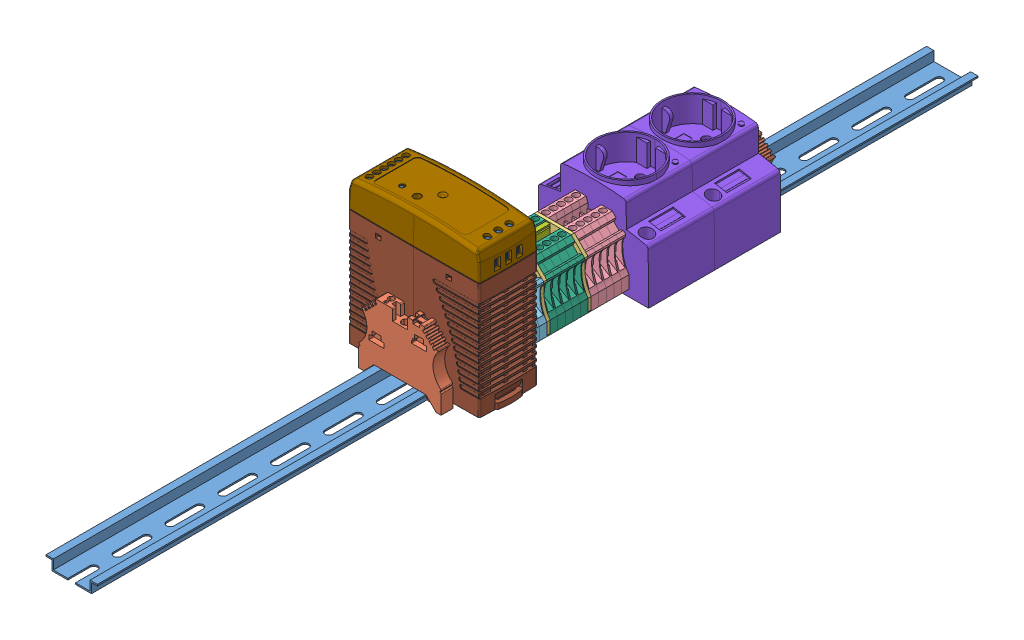
SolidWorks assembly 5xLNPE_Schuko-Raspi, configuration Standard. Lengths in mm.
Overall size (91.72 108.8 600).
29 component instances, 11 part files, 81 mates.
Components (placement in the parent):
- Hutschiene-1: Hutschiene [600] at (-17.5 -7.5 -600) size (35 7.5 600)
- WEW_35_2-1: WEW_35_2 [Standard] at (-45.75 -7 -453.6811) x (0 0 1) z (0 1 0) size (8 56.1 46.5)
- WEW_35_2-2: WEW_35_2 [Standard] at (10.35 -7 -223.8311) x (0 0 -1) z (0 1 0) size (8 56.1 46.5)
- D_UT_2.5_10-1: D_UT_2.5_10 [Standard] at (-46.4297 58.45 -274.0311) size (47 39.8 2.2)
- D_UT_2.5_10-2: D_UT_2.5_10 [Standard] at (-46.4297 58.45 -301.9811) size (47 39.8 2.2)
- D_UT_2.5_10-3: D_UT_2.5_10 [Standard] at (-46.4297 58.45 -329.9311) size (47 39.8 2.2)
- UT_2.5_PE-1: UT_2.5_PE [Standard] at (-48.6989 10.6178 -329.9311) x (0.992546 -0.121869 0) z (0 0 1) size (49.27 50.96 5.15)
- UT_2.5_PE-2: UT_2.5_PE [Standard] at (-48.6989 10.6178 -335.0811) x (0.992546 -0.121869 0) z (0 0 1) size (49.27 50.96 5.15)
- UT_2.5_PE-3: UT_2.5_PE [Standard] at (-48.6989 10.6178 -340.2311) x (0.992546 -0.121869 0) z (0 0 1) size (49.27 50.96 5.15)
- UT_2.5_PE-4: UT_2.5_PE [Standard] at (-48.6989 10.6178 -345.3811) x (0.992546 -0.121869 0) z (0 0 1) size (49.27 50.96 5.15)
- UT_2.5_PE-5: UT_2.5_PE [Standard] at (-48.6989 10.6178 -350.5311) x (0.992546 -0.121869 0) z (0 0 1) size (49.27 50.96 5.15)
- UT_2.5-1: UT_2.5 [Standard] at (-48.6989 10.6178 -274.0311) x (0.992546 -0.121869 0) z (0 0 1) size (49.27 50.96 5.15)
- UT_2.5-2: UT_2.5 [Standard] at (-48.6989 10.6178 -279.1811) x (0.992546 -0.121869 0) z (0 0 1) size (49.27 50.96 5.15)
- UT_2.5-3: UT_2.5 [Standard] at (-48.6989 10.6178 -284.3311) x (0.992546 -0.121869 0) z (0 0 1) size (49.27 50.96 5.15)
- UT_2.5-4: UT_2.5 [Standard] at (-48.6989 10.6178 -289.4811) x (0.992546 -0.121869 0) z (0 0 1) size (49.27 50.96 5.15)
- UT_2.5-5: UT_2.5 [Standard] at (-48.6989 10.6178 -294.6311) x (0.992546 -0.121869 0) z (0 0 1) size (49.27 50.96 5.15)
- UT_2.5_BU-1: UT_2.5_BU [Standard] at (-48.6989 10.6178 -301.9811) x (0.992546 -0.121869 0) z (0 0 1) size (49.27 50.96 5.15)
- UT_2.5_BU-2: UT_2.5_BU [Standard] at (-48.6989 10.6178 -307.1311) x (0.992546 -0.121869 0) z (0 0 1) size (49.27 50.96 5.15)
- UT_2.5_BU-3: UT_2.5_BU [Standard] at (-48.6989 10.6178 -312.2811) x (0.992546 -0.121869 0) z (0 0 1) size (49.27 50.96 5.15)
- UT_2.5_BU-4: UT_2.5_BU [Standard] at (-48.6989 10.6178 -317.4311) x (0.992546 -0.121869 0) z (0 0 1) size (49.27 50.96 5.15)
- UT_2.5_BU-5: UT_2.5_BU [Standard] at (-48.6989 10.6178 -322.5811) x (0.992546 -0.121869 0) z (0 0 1) size (49.27 50.96 5.15)
- FBS_5_5-1: FBS_5_5 [Standard] at (-24.1072 48.875 -332.8661) size (3 22.98 24.6)
- FBS_5_5-2: FBS_5_5 [Standard] at (-24.1072 48.875 -360.8161) size (3 22.98 24.6)
- EO_CF_UT_LED-1: EO_CF_UT_LED [Standard] at (-87.0914 -21.0563 -380.4311) size (75.48 61.64 45)
- EO_CF_UT_LED-2: EO_CF_UT_LED [Standard] at (-87.0914 -21.0563 -425.4311) size (75.48 61.64 45)
- MDR-40&60-1: MDR-40&60 [Standard] at (-16.4956 35.1498 -251.6915) x (0 0 1) z (0 1 0) size (40 91.72 100.24)
  - Skin_Group1-1: Skin_Group1 [Standard] at origin size (40 89.9 28.74)
  - 3P-CONECT-1: 3P-CONECT [Standard] at (-7.6496 -37.3548 41.6035) x (-1 0 0) z (0 1 0) size (34.1 93.54 85.1)
  - Skin_Group1.1-1: Skin_Group1.1 [Standard] at origin size (40 91.72 79.25)
Mates (geometry in assembly coordinates):
- Deckungsgleich1: coincident aligned: plane of Hutschiene-1 through (-17.5 -7.5 0) normal (0 0 1); plane of assembly through (0 0 0) normal (0 0 1)
- Deckungsgleich2: coincident aligned: plane of Hutschiene-1 through (-30 0 0) normal (0 1 0); plane of assembly through (0 0 0) normal (0 1 0)
- Deckungsgleich3: coincident aligned: plane of Hutschiene-1 through (0 -1 0) normal (1 0 0); plane of assembly through (0 0 0) normal (1 0 0)
- Deckungsgleich70: coincident anti-aligned: plane of Hutschiene-1 through (0 0 0) normal (0 1 0); plane of EO_CF_UT_LED-1 through (-54.05 0 -382.5811) normal (0 -1 0)
- Deckungsgleich71: coincident anti-aligned: plane of Hutschiene-1 through (-30 0 0) normal (0 1 0); plane of EO_CF_UT_LED-2 through (-54.05 0 -427.5811) normal (0 -1 0)
- Deckungsgleich72: coincident anti-aligned: plane of Hutschiene-1 through (-30 0 0) normal (0 1 0); plane of ? through (-54.05 0 -283.75) normal (0 -1 0)
- Deckungsgleich73: coincident anti-aligned: plane of Hutschiene-1 through (0 -1 0) normal (1 0 0); plane of EO_CF_UT_LED-1 through (0 8.9 -356.6811) normal (-1 0 0)
- Deckungsgleich74: coincident anti-aligned: plane of Hutschiene-1 through (0 -1 0) normal (1 0 0); plane of EO_CF_UT_LED-2 through (0 8.9 -401.6811) normal (-1 0 0)
- Deckungsgleich75: coincident anti-aligned: plane of Hutschiene-1 through (0 -1 0) normal (1 0 0); plane of ? through (0 8.9 -257.85) normal (-1 0 0)
- Deckungsgleich77: coincident anti-aligned: plane of EO_CF_UT_LED-1 through (-17.75 2.45 -400.6811) normal (0 0 -1); plane of EO_CF_UT_LED-2 through (-17.75 2.45 -400.6811) normal (0 0 1)
- Deckungsgleich78: coincident anti-aligned: plane of EO_CF_UT_LED-2 through (-17.75 2.45 -256.85) normal (0 0 -1); plane of ? through (-17.75 2.45 -256.85) normal (0 0 1)
- Deckungsgleich81: coincident anti-aligned: plane of Hutschiene-1 through (-30 0 0) normal (0 1 0); plane of WEW_35_2-2 through (-14.3966 13.4591 -231.876) normal (0 -1 0)
- Deckungsgleich82: coincident anti-aligned: plane of Hutschiene-1 through (-30 0 0) normal (0 1 0); plane of UT_2.5-1 through (-7.7 0 -274.0311) normal (0 -1 0)
- Deckungsgleich83: coincident anti-aligned: plane of Hutschiene-1 through (-30 0 0) normal (0 1 0); plane of UT_2.5-2 through (-7.7 0 -279.1811) normal (0 -1 0)
- Deckungsgleich84: coincident anti-aligned: plane of Hutschiene-1 through (-30 0 0) normal (0 1 0); plane of UT_2.5-3 through (-7.7 0 -284.3311) normal (0 -1 0)
- Deckungsgleich85: coincident anti-aligned: plane of Hutschiene-1 through (-30 0 0) normal (0 1 0); plane of UT_2.5-4 through (-7.7 0 -289.4811) normal (0 -1 0)
- Deckungsgleich86: coincident anti-aligned: plane of Hutschiene-1 through (-30 0 0) normal (0 1 0); plane of UT_2.5-5 through (-7.7 0 -294.6311) normal (0 -1 0)
- Deckungsgleich87: coincident aligned: plane of D_UT_2.5_10-1 through (4.3 30.8 -272.9311) normal (1 0 0); plane of UT_2.5-1 through (4.3 30.8 -274.0311) normal (1 0 0)
- Deckungsgleich88: coincident aligned: line of D_UT_2.5_10-1 through (4.3 29.6 -274.0311) axis (0 0 1); line of UT_2.5-1 through (4.3 29.6 -279.1811) axis (0 0 1)
- Deckungsgleich89: coincident anti-aligned: plane of D_UT_2.5_10-1 through (8.926 -3.78 -274.0311) normal (0 0 -1); plane of UT_2.5-1 through (0 0 -274.0311) normal (0 0 1)
- Deckungsgleich90: coincident anti-aligned: plane of UT_2.5-1 through (0 0 -279.1811) normal (0 0 -1); plane of UT_2.5-2 through (0 0 -279.1811) normal (0 0 1)
- Deckungsgleich91: coincident anti-aligned: plane of UT_2.5-2 through (0 0 -284.3311) normal (0 0 -1); plane of UT_2.5-3 through (0 0 -284.3311) normal (0 0 1)
- Deckungsgleich92: coincident anti-aligned: plane of UT_2.5-3 through (0 0 -289.4811) normal (0 0 -1); plane of UT_2.5-4 through (0 0 -289.4811) normal (0 0 1)
- Deckungsgleich93: coincident anti-aligned: plane of UT_2.5-4 through (0 0 -294.6311) normal (0 0 -1); plane of UT_2.5-5 through (0 0 -294.6311) normal (0 0 1)
- Deckungsgleich94: coincident anti-aligned: plane of Hutschiene-1 through (0 -1 0) normal (1 0 0); plane of UT_2.5-1 through (0 -1.1 -274.0311) normal (-1 0 0)
- Deckungsgleich95: coincident anti-aligned: plane of Hutschiene-1 through (0 -1 0) normal (1 0 0); plane of UT_2.5-2 through (0 -1.1 -279.1811) normal (-1 0 0)
- Deckungsgleich96: coincident anti-aligned: plane of Hutschiene-1 through (0 -1 0) normal (1 0 0); plane of UT_2.5-3 through (0 -1.1 -284.3311) normal (-1 0 0)
- Deckungsgleich97: coincident anti-aligned: plane of Hutschiene-1 through (0 -1 0) normal (1 0 0); plane of UT_2.5-4 through (0 -1.1 -289.4811) normal (-1 0 0)
- Deckungsgleich98: coincident anti-aligned: plane of Hutschiene-1 through (0 -1 0) normal (1 0 0); plane of UT_2.5-5 through (0 -1.1 -294.6311) normal (-1 0 0)
- Deckungsgleich101: coincident: plane of Hutschiene-1 through (0 -1 0) normal (1 0 0); line of WEW_35_2-2 through (21.0034 13.4591 -231.876) axis (0 0 1)
- Deckungsgleich102: coincident anti-aligned: plane of UT_2.5-1 through (-18.35 21.85 -274.5061) normal (0 0 -1); plane of FBS_5_5-1 through (-18.5 39.7 -274.5061) normal (0 0 1)
- Deckungsgleich103: coincident anti-aligned: plane of UT_2.5-2 through (-21.5 36.703 -279.1811) normal (1 0 0); plane of FBS_5_5-1 through (-21.5 38.7586 -288.4406) normal (-1 0 0)
- Deckungsgleich104: coincident aligned: plane of UT_2.5-1 through (-30.1 40 -274.0311) normal (0 1 0); plane of FBS_5_5-1 through (-18.5 40 -284.9061) normal (0 1 0)
- Deckungsgleich105: coincident anti-aligned: plane of D_UT_2.5_10-2 through (8.926 -3.78 -301.9811) normal (0 0 -1); plane of UT_2.5_BU-1 through (0 0 -301.9811) normal (0 0 1)
- Deckungsgleich106: coincident anti-aligned: plane of UT_2.5_BU-1 through (0 0 -307.1311) normal (0 0 -1); plane of UT_2.5_BU-2 through (0 0 -307.1311) normal (0 0 1)
- Deckungsgleich107: coincident anti-aligned: plane of UT_2.5_BU-2 through (0 0 -312.2811) normal (0 0 -1); plane of UT_2.5_BU-3 through (0 0 -312.2811) normal (0 0 1)
- Deckungsgleich108: coincident anti-aligned: plane of UT_2.5_BU-3 through (0 0 -317.4311) normal (0 0 -1); plane of UT_2.5_BU-4 through (0 0 -317.4311) normal (0 0 1)
- Deckungsgleich109: coincident anti-aligned: plane of UT_2.5_BU-4 through (0 0 -322.5811) normal (0 0 -1); plane of UT_2.5_BU-5 through (0 0 -322.5811) normal (0 0 1)
- Deckungsgleich110: coincident anti-aligned: plane of Hutschiene-1 through (-30 0 0) normal (0 1 0); plane of UT_2.5_BU-1 through (-7.7 0 -301.9811) normal (0 -1 0)
- Deckungsgleich111: coincident anti-aligned: plane of Hutschiene-1 through (-30 0 0) normal (0 1 0); plane of UT_2.5_BU-2 through (-7.7 0 -307.1311) normal (0 -1 0)
- Deckungsgleich112: coincident anti-aligned: plane of Hutschiene-1 through (-30 0 0) normal (0 1 0); plane of UT_2.5_BU-3 through (-7.7 0 -312.2811) normal (0 -1 0)
- Deckungsgleich113: coincident anti-aligned: plane of Hutschiene-1 through (-30 0 0) normal (0 1 0); plane of UT_2.5_BU-4 through (-7.7 0 -317.4311) normal (0 -1 0)
- Deckungsgleich114: coincident anti-aligned: plane of Hutschiene-1 through (-30 0 0) normal (0 1 0); plane of UT_2.5_BU-5 through (-7.7 0 -322.5811) normal (0 -1 0)
- Deckungsgleich115: coincident aligned: plane of D_UT_2.5_10-2 through (4.3 30.8 -300.8811) normal (1 0 0); plane of UT_2.5_BU-1 through (4.3 30.8 -301.9811) normal (1 0 0)
- Deckungsgleich116: coincident aligned: line of D_UT_2.5_10-2 through (4.3 29.6 -301.9811) axis (0 0 1); line of UT_2.5_BU-1 through (4.3 29.6 -307.1311) axis (0 0 1)
- Deckungsgleich117: coincident anti-aligned: plane of Hutschiene-1 through (0 -1 0) normal (1 0 0); plane of UT_2.5_BU-1 through (0 -1.1 -301.9811) normal (-1 0 0)
- Deckungsgleich118: coincident anti-aligned: plane of Hutschiene-1 through (0 -1 0) normal (1 0 0); plane of UT_2.5_BU-2 through (0 -1.1 -307.1311) normal (-1 0 0)
- Deckungsgleich119: coincident anti-aligned: plane of Hutschiene-1 through (0 -1 0) normal (1 0 0); plane of UT_2.5_BU-3 through (0 -1.1 -312.2811) normal (-1 0 0)
- Deckungsgleich120: coincident anti-aligned: plane of Hutschiene-1 through (0 -1 0) normal (1 0 0); plane of UT_2.5_BU-4 through (0 -1.1 -317.4311) normal (-1 0 0)
- Deckungsgleich121: coincident anti-aligned: plane of Hutschiene-1 through (0 -1 0) normal (1 0 0); plane of UT_2.5_BU-5 through (0 -1.1 -322.5811) normal (-1 0 0)
- Deckungsgleich122: coincident anti-aligned: plane of D_UT_2.5_10-2 through (-31.3534 31.331 -299.7811) normal (0 0 1); plane of UT_2.5-5 through (0 0 -299.7811) normal (0 0 -1)
- Deckungsgleich123: coincident anti-aligned: plane of UT_2.5_BU-1 through (-18.35 21.85 -302.4561) normal (0 0 -1); plane of FBS_5_5-2 through (-18.5 39.7 -302.4561) normal (0 0 1)
- Deckungsgleich124: coincident anti-aligned: plane of UT_2.5_BU-1 through (-21.5 36.703 -301.9811) normal (1 0 0); plane of FBS_5_5-2 through (-21.5 38.7586 -316.3906) normal (-1 0 0)
- Deckungsgleich125: coincident aligned: plane of UT_2.5_BU-1 through (-30.1 40 -301.9811) normal (0 1 0); plane of FBS_5_5-2 through (-18.5 40 -312.8561) normal (0 1 0)
- Deckungsgleich126: coincident anti-aligned: plane of D_UT_2.5_10-3 through (8.926 -3.78 -329.9311) normal (0 0 -1); plane of UT_2.5_PE-1 through (0 0 -329.9311) normal (0 0 1)
- Deckungsgleich127: coincident anti-aligned: plane of UT_2.5_PE-1 through (0 0 -335.0811) normal (0 0 -1); plane of UT_2.5_PE-2 through (0 0 -335.0811) normal (0 0 1)
- Deckungsgleich128: coincident anti-aligned: plane of UT_2.5_PE-2 through (0 0 -340.2311) normal (0 0 -1); plane of UT_2.5_PE-3 through (0 0 -340.2311) normal (0 0 1)
- Deckungsgleich129: coincident anti-aligned: plane of UT_2.5_PE-3 through (0 0 -345.3811) normal (0 0 -1); plane of UT_2.5_PE-4 through (0 0 -345.3811) normal (0 0 1)
- Deckungsgleich130: coincident anti-aligned: plane of UT_2.5_PE-4 through (0 0 -350.5311) normal (0 0 -1); plane of UT_2.5_PE-5 through (0 0 -350.5311) normal (0 0 1)
- Deckungsgleich131: coincident aligned: plane of D_UT_2.5_10-3 through (4.3 30.8 -328.8311) normal (1 0 0); plane of UT_2.5_PE-1 through (4.3 30.8 -329.9311) normal (1 0 0)
- Deckungsgleich132: coincident aligned: line of D_UT_2.5_10-3 through (4.3 30.8 -329.9311) axis (0 0 1); line of UT_2.5_PE-1 through (4.3 30.8 -335.0811) axis (0 0 1)
- Deckungsgleich133: coincident anti-aligned: plane of Hutschiene-1 through (-30 0 0) normal (0 1 0); plane of UT_2.5_PE-5 through (-7.7 0 -350.5311) normal (0 -1 0)
- Deckungsgleich134: coincident anti-aligned: plane of Hutschiene-1 through (-30 0 0) normal (0 1 0); plane of UT_2.5_PE-4 through (-7.7 0 -345.3811) normal (0 -1 0)
- Deckungsgleich135: coincident anti-aligned: plane of Hutschiene-1 through (-30 0 0) normal (0 1 0); plane of UT_2.5_PE-3 through (-7.7 0 -340.2311) normal (0 -1 0)
- Deckungsgleich136: coincident anti-aligned: plane of Hutschiene-1 through (-30 0 0) normal (0 1 0); plane of UT_2.5_PE-2 through (-7.7 0 -335.0811) normal (0 -1 0)
- Deckungsgleich137: coincident anti-aligned: plane of Hutschiene-1 through (-30 0 0) normal (0 1 0); plane of UT_2.5_PE-1 through (-7.7 0 -329.9311) normal (0 -1 0)
- Deckungsgleich138: coincident anti-aligned: plane of Hutschiene-1 through (0 -1 0) normal (1 0 0); plane of UT_2.5_PE-1 through (0 -1.1 -329.9311) normal (-1 0 0)
- Deckungsgleich139: coincident anti-aligned: plane of Hutschiene-1 through (0 -1 0) normal (1 0 0); plane of UT_2.5_PE-2 through (0 -1.1 -335.0811) normal (-1 0 0)
- Deckungsgleich140: coincident anti-aligned: plane of Hutschiene-1 through (0 -1 0) normal (1 0 0); plane of UT_2.5_PE-3 through (0 -1.1 -340.2311) normal (-1 0 0)
- Deckungsgleich141: coincident anti-aligned: plane of Hutschiene-1 through (0 -1 0) normal (1 0 0); plane of UT_2.5_PE-4 through (0 -1.1 -345.3811) normal (-1 0 0)
- Deckungsgleich142: coincident anti-aligned: plane of Hutschiene-1 through (0 -1 0) normal (1 0 0); plane of UT_2.5_PE-5 through (0 -1.1 -350.5311) normal (-1 0 0)
- Deckungsgleich143: coincident anti-aligned: plane of D_UT_2.5_10-3 through (-31.3534 31.331 -327.7311) normal (0 0 1); plane of UT_2.5_BU-5 through (0 0 -327.7311) normal (0 0 -1)
- Deckungsgleich144: coincident anti-aligned: plane of UT_2.5_PE-5 through (0 0 -355.6811) normal (0 0 -1); plane of EO_CF_UT_LED-1 through (-17.75 2.45 -355.6811) normal (0 0 1)
- Deckungsgleich145: coincident: plane of WEW_35_2-1 through (-17.7 0 -301.85) normal (0 0 1); plane of ? through (-17.75 2.45 -301.85) normal (0 0 -1)
- Deckungsgleich146: coincident anti-aligned: plane of Hutschiene-1 through (0 0 0) normal (0 1 0); plane of WEW_35_2-1 through (0 0 -445.6811) normal (0 -1 0)
- Deckungsgleich147: coincident anti-aligned: line of Hutschiene-1 through (0 0 0) axis (0 0 -1); line of WEW_35_2-1 through (0 0 -453.6811) axis (0 0 1)
- Deckungsgleich148: coincident anti-aligned: plane of WEW_35_2-1 through (-17.7 0 -445.6811) normal (0 0 1); plane of EO_CF_UT_LED-2 through (-17.75 2.45 -445.6811) normal (0 0 -1)
- Deckungsgleich149: coincident aligned: plane of Hutschiene-1 through (0 0 0) normal (0 1 0); plane of MDR-40&60-1/Skin_Group1.1-1 through (27.0045 0 -231.331) normal (0 1 0)
- Deckungsgleich150: coincident anti-aligned: plane of Hutschiene-1 through (0 -1 0) normal (1 0 0); plane of MDR-40&60-1/Skin_Group1.1-1 through (0 0.0063 -259.4363) normal (-1 0 0)
- Tangential1: tangent anti-aligned: plane of D_UT_2.5_10-1 through (-31.3534 31.331 -271.8311) normal (0 0 1); cylinder of MDR-40&60-1/Skin_Group1.1-1 through (-16.4456 -4.3965 3095.823) axis (0 1 0) radius 3367.6541
- Tangential2: tangent anti-aligned: plane of WEW_35_2-2 through (-17.7 0 -231.8311) normal (0 0 -1); cylinder of MDR-40&60-1/Skin_Group1.1-1 through (-16.4456 -4.3965 -3599.4852) axis (0 1 0) radius 3367.6541
